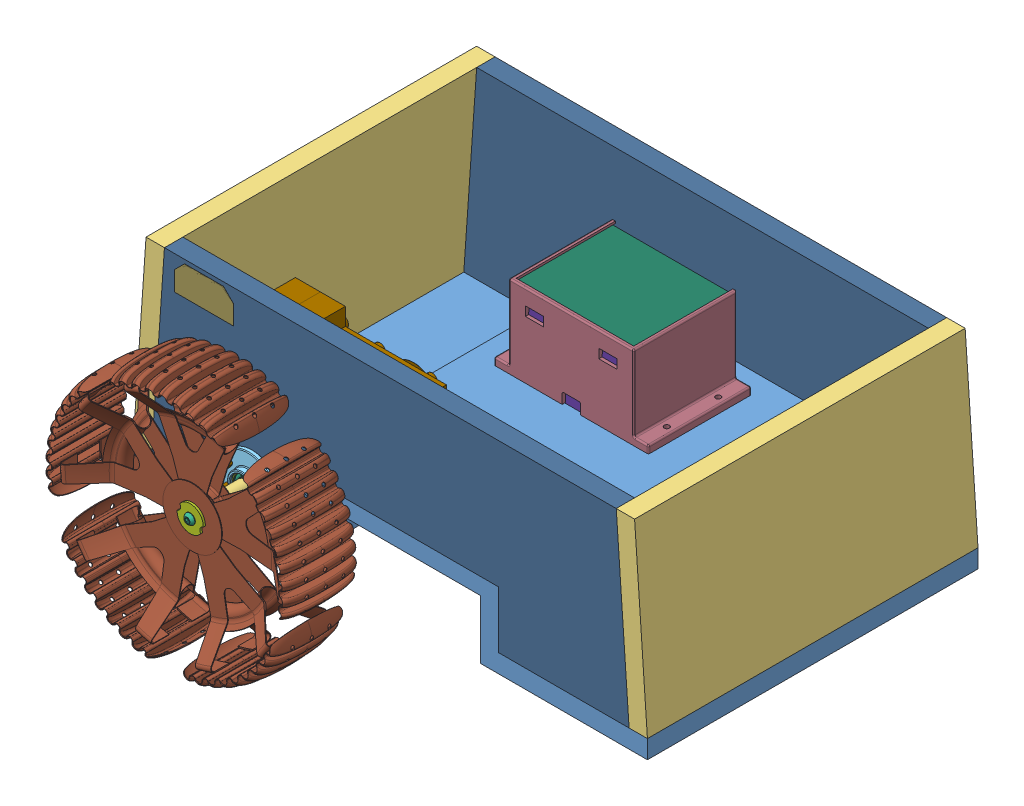
SolidWorks assembly ROVER_config69, configuration Default. Lengths in mm.
Overall size (711.63 387.84 571.91).
76 component instances, 35 part files, 27 mates.
Components (placement in the parent):
- Plancher-1: Plancher [Default] at (-314.6501 422.5882 577.2661) size (700 105 450)
- 01-Anneau_separation-1: 01-Anneau_separation [Default] at (38.152 502.5882 794.9914) x (0.982803 0 -0.184657) z (-0.184657 0 -0.982803) size (228.6 10 228.6)
- Mur_largeur-1: Mur_largeur [Default] at (-314.6501 447.5882 577.2661) size (42.54 250 450)
- Mur_largeur-2: Mur_largeur [Default] at (385.3499 447.5882 1027.2661) x (-1 0 0) z (0 0 -1) size (42.54 250 450)
- PB2023-M054 DRIVETRAIN ASSEMBLY-1: PB2023-M054 DRIVETRAIN ASSEMBLY [Default] at (-152.1501 480.5882 991.7661) x (0 1 0) z (0 0 1) size (93.83 80 344.65)
  - A12220103_FRONT_BRACKET_ASSEMBLY-1: A12220103_FRONT_BRACKET_ASSEMBLY [Default] at origin size (86 80 534.65)
    - 12220105_SUPPORT_BRACKET-1: 12220105_SUPPORT_BRACKET [Default] at (-52 -128.9256 -192.9876) x (0 0 -1) z (1 0 0) size (160.65 80 80)
    - A12220101_FRONT_CASE_ASSEMBLY-1: A12220101_FRONT_CASE_ASSEMBLY [Default] at origin size (78 78 141.2)
      - 12220103_FRONT_HOUSING-1: 12220103_FRONT_HOUSING [Default] at (-52 141.0744 -192.9876) x (0 0 -1) z (1 0 0) size (60 78 78)
      - BALL BEARING-1: BALL BEARING [6656K203] at origin size (32 32 10)
      - BALL BEARING-2: BALL BEARING [6656K203] at (0 0 41) size (32 32 10)
      - Internal Retaining Ring (98455A129)-1: Internal Retaining Ring (98455A129) [98455A129] at (0.0361 0.7992 46) x (0.998982 -0.045107 0) z (0 0 1) size (34.4 33.81 1.2)
    - M6 x 20mm Steel Hex Head Screw (91310A333)-2: M6 x 20mm Steel Hex Head Screw (91310A333) [91310A333] at (-15.125 -26.1973 37.15) x (0 0 1) z (-0.44141 0.897306 0) size (24.4 11.55 10)
    - M6 x 1mm Steel Hex LockNut (90592A016)-1: M6 x 1mm Steel Hex LockNut (90592A016) [97260A101] at (15.125 -26.1973 41.85) x (0.928554 -0.371196 0) z (-0.371196 -0.928554 0) size (10 8.38 11.55)
    - 20MM External Retaining Ring (98541A123)-4: 20MM External Retaining Ring (98541A123) [98541A123] at (0 0 92.94) x (0 0 1) z (-0.186581 0.98244 0) size (1.2 25.1 22.76)
    - A12220110_FRONT_SHAFT_ASSEMBLY-1: A12220110_FRONT_SHAFT_ASSEMBLY [Default] at (1.7896 0 -19.01) x (0 -1 0) z (0 0 1) size (78 67.32 307.03)
      - A12220105_MOTOR_BRACKET_ASSEMBLY-1: A12220105_MOTOR_BRACKET_ASSEMBLY [Default] at origin size (78 67.32 280.24) (flexible)
        - 12220106_MOTOR_BRACKET-1: 12220106_MOTOR_BRACKET [Default] at (0 -2.2046 8.53) size (78 52.48 69.85)
        - 12220106-051 MiniCIM Motor Assembly-1: 12220106-051 MiniCIM Motor Assembly [Default] at origin size (64.01 67.32 218.97)
          - Gearbox Assembly-1: Gearbox Assembly [Default] at (34.0244 -12.4567 -92.7758) x (0 0 1) z (-1 0 0) size (123.35 56.32 44.45)
            - Output Housing-2: Output Housing [Default] at (64.8023 -0.856 18.2213) x (1 0 0) z (0 -1 0) size (75.7 44.45 56.32)
              - Housing-1: Housing [Default] at (19.8785 -6.4219 -11.5232) size (18.13 44.45 42)
              - Encoder.step-1: Encoder.step [Default] at (12.6785 15.8031 -11.5232) x (0 0 1) z (-1 0 0) size (56.32 42 21.21)
              - Gearbox_output_shaft-1: Gearbox_output_shaft [Default] at origin size (63.51 17 17)
            - Ring Gears-1: Ring Gears [Default] at (71.9808 10.6671 11.7994) x (1 0 0) z (0 -1 0) size (32.2 42 42)
            - Ring Gear Stage 3-1: Ring Gear Stage 3 [Default] at (59.2808 10.6671 11.7994) x (1 0 0) z (0 -1 0) size (28.65 42 42)
          - CIM Adaptor.step-1: CIM Adaptor.step [Default] at (0 -1.7896 -68.72) x (0 -1 0) z (-1 0 0) size (64.01 21.63 64.01)
          - Mini CIM-1: Mini CIM [Default] at (0 -1.7896 -80.245) x (0 0 -1) z (1 0 0) size (101.22 64.01 64.01)
          - 8-32 X 3IN LG - Black-Oxide Alloy Steel Socket Head Screw (90044A516)-1: 8-32 X 3IN LG - Black-Oxide Alloy Steel Socket Head Screw (90044A516) [90044A516] at (17.5 15.7104 -75.245) x (-0.08536 0.99635 0) z (0 0 -1) size (6.86 6.86 81.33)
          - 8-32 X 3IN LG - Black-Oxide Alloy Steel Socket Head Screw (90044A516)-3: 8-32 X 3IN LG - Black-Oxide Alloy Steel Socket Head Screw (90044A516) [90044A516] at (-17.5 -19.2896 -75.245) x (-0.242255 0.970213 0) z (0 0 -1) size (6.86 6.86 81.33)
        - 10-32 X 0.875IN LG - Black-Oxide Alloy Steel Socket Head Screw (91251A346)-1: 10-32 X 0.875IN LG - Black-Oxide Alloy Steel Socket Head Screw (91251A346) [91251A346] at (-17.9605 16.1709 6.1805) x (0.130335 0.99147 0) z (0 0 1) size (7.94 7.94 27.67)
        - 10-32 X 0.875IN LG - Black-Oxide Alloy Steel Socket Head Screw (91251A346)-2: 10-32 X 0.875IN LG - Black-Oxide Alloy Steel Socket Head Screw (91251A346) [91251A346] at (17.9605 -19.7501 6.1805) x (0.872398 0.488796 0) z (0 0 1) size (7.94 7.94 27.67)
      - PB2023-M005 ROTARY SHAFT-1: PB2023-M005 ROTARY SHAFT [Default] at (0 -1.7896 136.57) x (0 0 -1) z (1 0 0) size (126.56 25 25)
      - 12220110_MOTOR_KEY-1: 12220110_MOTOR_KEY [Default] at (0 5.1764 16.3975) size (3.17 4.76 26.16)
    - M6 x 20mm Steel Hex Head Screw (91310A333)-7: M6 x 20mm Steel Hex Head Screw (91310A333) [91310A333] at (15.125 -26.1973 37.15) x (0 0 1) z (0.78025 0.625468 0) size (24.4 11.55 10)
    - M6 x 20mm Steel Hex Head Screw (91310A333)-9: M6 x 20mm Steel Hex Head Screw (91310A333) [91310A333] at (15.125 26.1973 37.15) x (0 0 1) z (0.877007 0.480477 0) size (24.4 11.55 10)
    - M6 x 20mm Steel Hex Head Screw (91310A333)-11: M6 x 20mm Steel Hex Head Screw (91310A333) [91310A333] at (-15.0958 26.1466 37.15) x (0 0 1) z (0.947118 0.320887 0) size (24.4 11.55 10)
    - M6 x 1mm Steel Hex LockNut (90592A016)-7: M6 x 1mm Steel Hex LockNut (90592A016) [97260A101] at (-15.125 -26.1973 41.85) x (0.975663 -0.219276 0) z (-0.219276 -0.975663 0) size (10 8.38 11.55)
    - M6 x 1mm Steel Hex LockNut (90592A016)-9: M6 x 1mm Steel Hex LockNut (90592A016) [97260A101] at (-15.125 26.1973 41.85) x (0.995642 -0.093258 0) z (-0.093258 -0.995642 0) size (10 8.38 11.55)
    - M6 x 1mm Steel Hex LockNut (90592A016)-11: M6 x 1mm Steel Hex LockNut (90592A016) [97260A101] at (15.2049 26.151 41.85) x (1 -0.000046 0) z (-0.000046 -1 0) size (10 8.38 11.55)
  - M6 x 25mm Steel Socket Head Screw (91290A330)-1: M6 x 25mm Steel Socket Head Screw (91290A330) [91290A330] at (-31.155 30 -64.48) x (0 -0.901175 -0.433456) z (1 0 0) size (10 10 31.46)
  - M6 x 25mm Steel Socket Head Screw (91290A330)-2: M6 x 25mm Steel Socket Head Screw (91290A330) [91290A330] at (-31.155 -30 -64.48) x (0 -0.15786 -0.987461) z (1 0 0) size (10 10 31.46)
  - M6 x 1mm Steel Hex LockNut (90592A016)-1: M6 x 1mm Steel Hex LockNut (90592A016) [97260A101] at (-33 -30 -64.48) x (0 0.608626 0.793457) z (0 -0.793457 0.608626) size (10 8.38 11.55)
  - M6 x 1mm Steel Hex LockNut (90592A016)-2: M6 x 1mm Steel Hex LockNut (90592A016) [97260A101] at (-33 30 -64.48) x (0 -0.994883 0.101031) z (0 -0.101031 -0.994883) size (10 8.38 11.55)
  - M8 X 20MM - 18-8 Stainless Steel Button Head Hex Drive Screws (97763A444)-1: M8 X 20MM - 18-8 Stainless Steel Button Head Hex Drive Screws (97763A444) [97763A444] at (0 0 124.825) x (0.999813 0.019347 0) z (0 0 1) size (14 14 25.15)
  - PB2023-M006 WHEEL END CAP CUSTOM WASHER-1: PB2023-M006 WHEEL END CAP CUSTOM WASHER [Default] at (0 0 117.56) x (0 0 -1) z (-0.345262 -0.938506 0) size (8.5 35.5 34.05)
  - 98870A743_Machine Key-1: 98870A743_Machine Key [98870A743] at (10 0 103.06) size (6 6 12)
- 02-Batterie-5: 02-Batterie [Default] at (-192.1501 585.2882 1002.2661) x (0 -1 0) z (1 0 0) size (137.7 155.1 34)
- 02-Batterie-6: 02-Batterie [Default] at (-226.1501 585.2882 1002.2661) x (0 -1 0) z (1 0 0) size (137.7 155.1 34)
- 02-Batterie-7: 02-Batterie [Default] at (-54.4501 527.5882 1002.2661) x (-1 0 0) z (0 -1 0) size (137.7 155.1 34)
- Mur_longueur-1: Mur_longueur [Default] at (-289.5891 447.5882 1002.2661) size (650 250 25)
- PB2023-M052 WHEEL ASSEMBLY-1: PB2023-M052 WHEEL ASSEMBLY [Default] at (-152.1501 480.5882 1097.3661) x (0.999779 0.021018 0) z (0 0 1) size (341.18 337.46 103.61)
- Mur_longueur-2: Mur_longueur [Default] at (-289.5891 447.5882 577.2661) size (650 250 25)
- QJ Solar Cell 4G32C-1: QJ Solar Cell 4G32C [Default] at (-218.1845 672.315 1027.4361) size (80 40 0.12)
- A12220113_ELECTRICAL_CONTROL_BOX-2: A12220113_ELECTRICAL_CONTROL_BOX [Default] at (27.9698 526.9187 588.4784) size (210 113.22 141.5)
  - 12220118_ELECTRICAL_BOX-1: 12220118_ELECTRICAL_BOX [Default] at (-29.7877 57.9976 190.2575) size (210 112.5 140)
  - 12220120_ELECTRICAL_BOX_OPENING_SLOT-1: 12220120_ELECTRICAL_BOX_OPENING_SLOT [Default] at (55.2123 57.9976 102.7575) x (-1 0 0) z (0 0 -1) size (30.6 54.5 6.5)
  - 12220119_ACRYLIC_SHEET-1: 12220119_ACRYLIC_SHEET [Default] at (55.2123 163.7976 170.2575) x (0 0 -1) z (1 0 0) size (135 2.8 165)
  - A12220112_SLOT_WITH_BRUSH-1: A12220112_SLOT_WITH_BRUSH [Default] at (-16.3066 139.0751 243.5929) x (0 0 -1) z (1 0 0) size (9.7 29.24 29.5)
    - 12220122_SLOT-1: 12220122_SLOT [Default] at (12.7854 19.2475 6.7689) size (9.7 11.4 29.5)
    - 12220121_BRUSH-1: 12220121_BRUSH [74405T911] at (9.9542 14.2475 21.5369) size (4.76 25.4 29.46)
  - A12220112_SLOT_WITH_BRUSH-2: A12220112_SLOT_WITH_BRUSH [Default] at (83.6934 139.0751 243.5929) x (0 0 -1) z (1 0 0) size (9.7 29.24 29.5)
    - 12220122_SLOT-1: 12220122_SLOT [Default] at (12.7854 19.2475 6.7689) size (9.7 11.4 29.5)
    - 12220121_BRUSH-1: 12220121_BRUSH [74405T911] at (9.9542 14.2475 21.5369) size (4.76 25.4 29.46)
  - A12220112_SLOT_WITH_BRUSH-3: A12220112_SLOT_WITH_BRUSH [Default] at (33.6934 62.8751 243.5929) x (0 0 -1) z (1 0 0) size (9.7 29.24 29.5)
    - 12220122_SLOT-1: 12220122_SLOT [Default] at (12.7854 19.2475 6.7689) size (9.7 11.4 29.5)
    - 12220121_BRUSH-1: 12220121_BRUSH [74405T911] at (9.9542 14.2475 21.5369) size (4.76 25.4 29.46)
  - A12220112_SLOT_WITH_BRUSH-4: A12220112_SLOT_WITH_BRUSH [Default] at (26.7312 139.0751 96.9221) x (0 0 1) z (-1 0 0) size (9.7 29.24 29.5)
    - 12220122_SLOT-1: 12220122_SLOT [Default] at (12.7854 19.2475 6.7689) size (9.7 11.4 29.5)
    - 12220121_BRUSH-1: 12220121_BRUSH [74405T911] at (9.9542 14.2475 21.5369) size (4.76 25.4 29.46)
  - A12220112_SLOT_WITH_BRUSH-5: A12220112_SLOT_WITH_BRUSH [Default] at (126.7312 139.0751 96.9221) x (0 0 1) z (-1 0 0) size (9.7 29.24 29.5)
    - 12220122_SLOT-1: 12220122_SLOT [Default] at (12.7854 19.2475 6.7689) size (9.7 11.4 29.5)
    - 12220121_BRUSH-1: 12220121_BRUSH [74405T911] at (9.9542 14.2475 21.5369) size (4.76 25.4 29.46)
  - A12220112_SLOT_WITH_BRUSH-6: A12220112_SLOT_WITH_BRUSH [Default] at (76.7312 117.8751 96.9221) x (0 0 1) z (-1 0 0) size (9.7 29.24 29.5)
    - 12220122_SLOT-1: 12220122_SLOT [Default] at (12.7854 19.2475 6.7689) size (9.7 11.4 29.5)
    - 12220121_BRUSH-1: 12220121_BRUSH [74405T911] at (9.9542 14.2475 21.5369) size (4.76 25.4 29.46)
Mates (geometry in assembly coordinates):
- Coincident5: coincident anti-aligned: plane of Plancher-1 through (-87.1501 502.5882 1027.2661) normal (0 -1 0); plane of 01-Anneau_separation-1 through (38.152 502.5882 794.9914) normal (0 1 0)
- Coincident6: coincident anti-aligned: plane of Plancher-1 through (-314.6501 447.5882 1027.2661) normal (0 1 0); plane of Mur_largeur-1 through (-289.5891 447.5882 1027.2661) normal (0 -1 0)
- Coincident7: coincident aligned: plane of Plancher-1 through (-314.6501 422.5882 1027.2661) normal (0 0 1); plane of Mur_largeur-1 through (-314.6501 447.5882 1027.2661) normal (0 0 1)
- Coincident8: coincident aligned: line of Plancher-1 through (-314.6501 447.5882 1027.2661) axis (0 0 -1); line of Mur_largeur-1 through (-314.6501 447.5882 1027.2661) axis (0 0 -1)
- Coincident9: coincident anti-aligned: plane of Plancher-1 through (385.3499 447.5882 1027.2661) normal (0 1 0); plane of Mur_largeur-2 through (360.2888 447.5882 577.2661) normal (0 -1 0)
- Coincident10: coincident aligned: plane of Plancher-1 through (-314.6501 422.5882 1027.2661) normal (0 0 1); plane of Mur_largeur-2 through (385.3499 447.5882 1027.2661) normal (0 0 1)
- Coincident11: coincident anti-aligned: line of Plancher-1 through (385.3499 447.5882 1027.2661) axis (0 0 -1); line of Mur_largeur-2 through (385.3499 447.5882 577.2661) axis (0 0 1)
- Coincident12: coincident anti-aligned: plane of Plancher-1 through (-314.6501 447.5882 1027.2661) normal (0 1 0); plane of PB2023-M054 DRIVETRAIN ASSEMBLY-1/A12220103_FRONT_BRACKET_ASSEMBLY-1/12220105_SUPPORT_BRACKET-1 through (-152.1501 447.5882 1027.2661) normal (0 -1 0)
- Coincident13: coincident aligned: plane of Plancher-1 through (-314.6501 422.5882 1027.2661) normal (0 0 1); plane of PB2023-M054 DRIVETRAIN ASSEMBLY-1/A12220103_FRONT_BRACKET_ASSEMBLY-1/12220105_SUPPORT_BRACKET-1 through (-192.1501 453.9382 1027.2661) normal (0 0 1)
- Coincident14: coincident anti-aligned: plane of Plancher-1 through (-112.1501 447.5882 1027.2661) normal (-1 0 0); plane of PB2023-M054 DRIVETRAIN ASSEMBLY-1/A12220103_FRONT_BRACKET_ASSEMBLY-1/12220105_SUPPORT_BRACKET-1 through (-112.1501 453.9382 1027.2661) normal (1 0 0)
- Coincident26: coincident anti-aligned: plane of PB2023-M054 DRIVETRAIN ASSEMBLY-1/A12220103_FRONT_BRACKET_ASSEMBLY-1/12220105_SUPPORT_BRACKET-1 through (-192.1501 453.9382 831.6161) normal (-1 0 0); plane of 02-Batterie-5 through (-192.1501 585.2882 860.9661) normal (1 0 0)
- Coincident27: coincident anti-aligned: plane of Plancher-1 through (-314.6501 447.5882 1027.2661) normal (0 1 0); plane of 02-Batterie-5 through (-192.1501 447.5882 860.9661) normal (0 -1 0)
- Coincident28: coincident anti-aligned: plane of Plancher-1 through (-314.6501 447.5882 1027.2661) normal (0 1 0); plane of 02-Batterie-6 through (-226.1501 447.5882 860.9661) normal (0 -1 0)
- Coincident29: coincident anti-aligned: plane of 02-Batterie-5 through (-226.1501 585.2882 860.9661) normal (-1 0 0); plane of 02-Batterie-6 through (-226.1501 585.2882 860.9661) normal (1 0 0)
- Coincident30: coincident aligned: plane of 02-Batterie-5 through (-192.1501 585.2882 1002.2661) normal (0 0 1); plane of 02-Batterie-6 through (-226.1501 585.2882 1002.2661) normal (0 0 1)
- Coincident31: coincident anti-aligned: plane of Plancher-1 through (-112.1501 527.5882 1027.2661) normal (0 1 0); plane of 02-Batterie-7 through (-54.4501 527.5882 860.9661) normal (0 -1 0)
- Coincident32: coincident anti-aligned: plane of 02-Batterie-5 through (-192.1501 585.2882 860.9661) normal (1 0 0); plane of 02-Batterie-7 through (-192.1501 527.5882 860.9661) normal (-1 0 0)
- Coincident33: coincident aligned: plane of 02-Batterie-5 through (-192.1501 585.2882 1002.2661) normal (0 0 1); plane of 02-Batterie-7 through (-54.4501 527.5882 1002.2661) normal (0 0 1)
- Coincident34: coincident anti-aligned: plane of Mur_largeur-1 through (-272.1074 697.5882 1027.2661) normal (0.997564 -0.069756 0); plane of Mur_longueur-1 through (-272.1074 697.5882 1027.2661) normal (-0.997564 0.069756 0)
- Coincident35: coincident aligned: plane of Mur_largeur-1 through (-314.6501 447.5882 1027.2661) normal (0 0 1); plane of Mur_longueur-1 through (-289.5891 447.5882 1027.2661) normal (0 0 1)
- Coincident36: coincident anti-aligned: plane of Plancher-1 through (-314.6501 447.5882 1027.2661) normal (0 1 0); plane of Mur_longueur-1 through (-289.5891 447.5882 1027.2661) normal (0 -1 0)
- Coincident37: coincident anti-aligned: plane of 02-Batterie-5 through (-192.1501 585.2882 1002.2661) normal (0 0 1); plane of Mur_longueur-1 through (-289.5891 447.5882 1002.2661) normal (0 0 -1)
- Concentric1: concentric anti-aligned: cylinder of PB2023-M054 DRIVETRAIN ASSEMBLY-1/A12220103_FRONT_BRACKET_ASSEMBLY-1/A12220110_FRONT_SHAFT_ASSEMBLY-1/PB2023-M005 ROTARY SHAFT-1 through (-152.1501 480.5882 1118.4672) axis (0 0 1) radius 10; cylinder of PB2023-M052 WHEEL ASSEMBLY-1 through (-152.1501 480.5882 1040.3786) axis (0 0 -1) radius 10.05
- Coincident38: coincident anti-aligned: plane of PB2023-M054 DRIVETRAIN ASSEMBLY-1/PB2023-M006 WHEEL END CAP CUSTOM WASHER-1 through (-146.0217 497.2467 1109.3261) normal (0 0 -1); plane of PB2023-M052 WHEEL ASSEMBLY-1 through (-152.1501 480.5882 1109.3261) normal (0 0 1)
- Coincident39: coincident anti-aligned: plane of Plancher-1 through (-314.6501 447.5882 1027.2661) normal (0 1 0); plane of Mur_longueur-2 through (-289.5891 447.5882 602.2661) normal (0 -1 0)
- Coincident40: coincident anti-aligned: plane of Mur_largeur-1 through (-272.1074 697.5882 1027.2661) normal (0.997564 -0.069756 0); plane of Mur_longueur-2 through (-272.1074 697.5882 602.2661) normal (-0.997564 0.069756 0)
- Coincident41: coincident aligned: plane of Plancher-1 through (-314.6501 422.5882 577.2661) normal (0 0 -1); plane of Mur_longueur-2 through (-289.5891 447.5882 577.2661) normal (0 0 -1)
